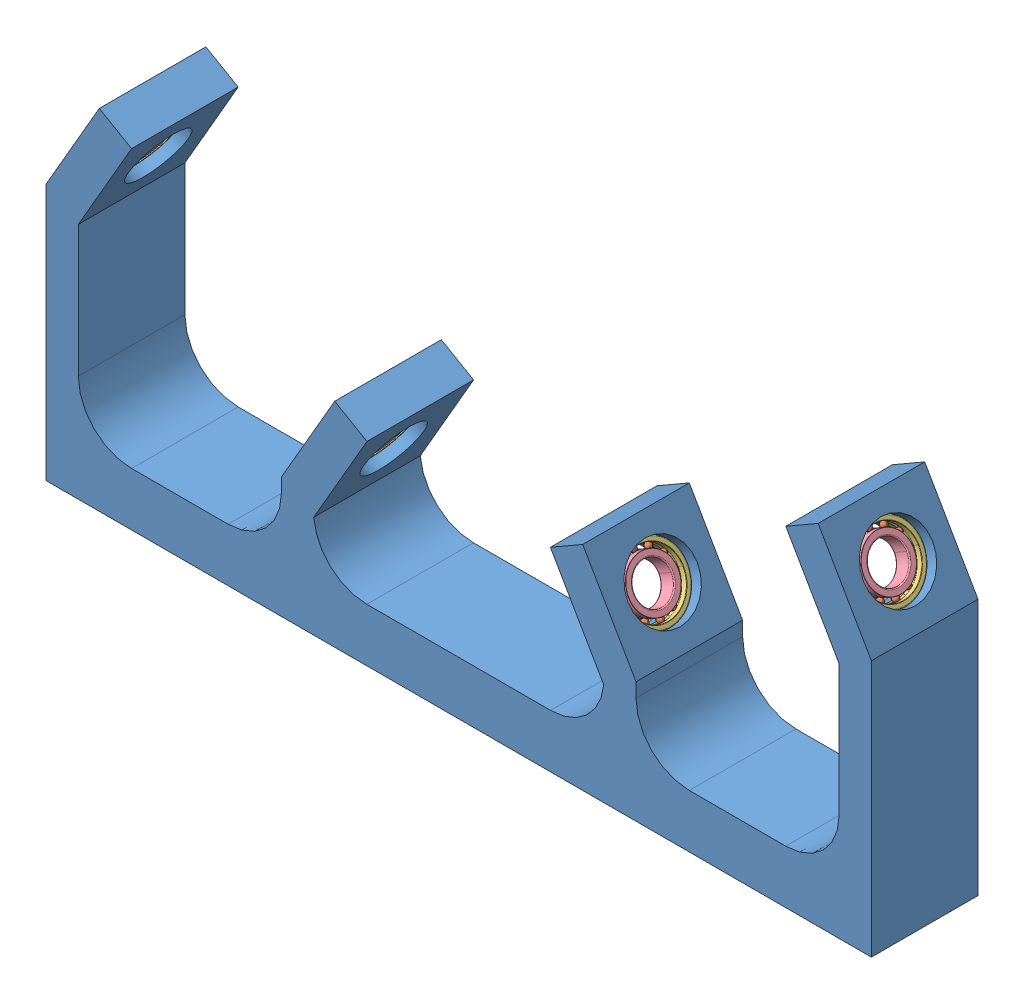
SolidWorks assembly Assemblage2, configuration Défaut. Lengths in mm.
Overall size (154.87 65.48 20).
61 component instances, 4 part files, 8 mates.
Components (placement in the parent):
- support rouleau-1: support rouleau [Défaut] at (-2.3977 -25.7602 154.8705) size (154.87 65.48 20)
- SKF_W_627_X-1: SKF_W_627_X [Default] at (-73.1009 15.0603 154.8705) x (0.866025 -0.5 0) z (0 0 1) size (3 13 13)
  - SKF_W_627_X_16-1: SKF_W_627_X_16 [Default] x (1 0 0) z (0 -0.5 0.866025) size (1.2 1.2 1.2)
  - SKF_W_627_X_16-2: SKF_W_627_X_16 [Default] x (1 0 0) z (0 -0.866025 0.5) size (1.2 1.2 1.2)
  - SKF_W_627_X_16-3: SKF_W_627_X_16 [Default] x (1 0 0) z (0 -1 0) size (1.2 1.2 1.2)
  - SKF_W_627_X_16-4: SKF_W_627_X_16 [Default] x (1 0 0) z (0 -0.866025 -0.5) size (1.2 1.2 1.2)
  - SKF_W_627_X_16-5: SKF_W_627_X_16 [Default] x (1 0 0) z (0 -0.5 -0.866025) size (1.2 1.2 1.2)
  - SKF_W_627_X_16-6: SKF_W_627_X_16 [Default] x (1 0 0) z (0 0 -1) size (1.2 1.2 1.2)
  - SKF_W_627_X_16-7: SKF_W_627_X_16 [Default] x (1 0 0) z (0 0.5 -0.866025) size (1.2 1.2 1.2)
  - SKF_W_627_X_16-8: SKF_W_627_X_16 [Default] x (1 0 0) z (0 0.866025 -0.5) size (1.2 1.2 1.2)
  - SKF_W_627_X_16-9: SKF_W_627_X_16 [Default] x (1 0 0) z (0 1 0) size (1.2 1.2 1.2)
  - SKF_W_627_X_16-10: SKF_W_627_X_16 [Default] x (1 0 0) z (0 0.866025 0.5) size (1.2 1.2 1.2)
  - SKF_W_627_X_16-11: SKF_W_627_X_16 [Default] x (1 0 0) z (0 0.5 0.866025) size (1.2 1.2 1.2)
  - SKF_W_627_X_16-12: SKF_W_627_X_16 [Default] at origin size (1.2 1.2 1.2)
  - SKF_W_627_X_29-1: SKF_W_627_X_29 [Default] at origin size (3 13 13)
  - SKF_W_627_X_31-1: SKF_W_627_X_31 [Default] at origin size (3 9.35 9.35)
- SKF_W_627_X-2: SKF_W_627_X [Default] at (21.5401 -11.9397 154.8705) x (0.866025 0.5 0) z (0 0 1) size (3 13 13)
  - SKF_W_627_X_16-1: SKF_W_627_X_16 [Default] x (1 0 0) z (0 -0.5 0.866025) size (1.2 1.2 1.2)
  - SKF_W_627_X_16-2: SKF_W_627_X_16 [Default] x (1 0 0) z (0 -0.866025 0.5) size (1.2 1.2 1.2)
  - SKF_W_627_X_16-3: SKF_W_627_X_16 [Default] x (1 0 0) z (0 -1 0) size (1.2 1.2 1.2)
  - SKF_W_627_X_16-4: SKF_W_627_X_16 [Default] x (1 0 0) z (0 -0.866025 -0.5) size (1.2 1.2 1.2)
  - SKF_W_627_X_16-5: SKF_W_627_X_16 [Default] x (1 0 0) z (0 -0.5 -0.866025) size (1.2 1.2 1.2)
  - SKF_W_627_X_16-6: SKF_W_627_X_16 [Default] x (1 0 0) z (0 0 -1) size (1.2 1.2 1.2)
  - SKF_W_627_X_16-7: SKF_W_627_X_16 [Default] x (1 0 0) z (0 0.5 -0.866025) size (1.2 1.2 1.2)
  - SKF_W_627_X_16-8: SKF_W_627_X_16 [Default] x (1 0 0) z (0 0.866025 -0.5) size (1.2 1.2 1.2)
  - SKF_W_627_X_16-9: SKF_W_627_X_16 [Default] x (1 0 0) z (0 1 0) size (1.2 1.2 1.2)
  - SKF_W_627_X_16-10: SKF_W_627_X_16 [Default] x (1 0 0) z (0 0.866025 0.5) size (1.2 1.2 1.2)
  - SKF_W_627_X_16-11: SKF_W_627_X_16 [Default] x (1 0 0) z (0 0.5 0.866025) size (1.2 1.2 1.2)
  - SKF_W_627_X_16-12: SKF_W_627_X_16 [Default] at origin size (1.2 1.2 1.2)
  - SKF_W_627_X_29-1: SKF_W_627_X_29 [Default] at origin size (3 13 13)
  - SKF_W_627_X_31-1: SKF_W_627_X_31 [Default] at origin size (3 9.35 9.35)
- SKF_W_627_X-3: SKF_W_627_X [Default] at (-28.9336 -10.4397 154.8705) x (0.866025 -0.5 0) z (0 0 1) size (3 13 13)
  - SKF_W_627_X_16-1: SKF_W_627_X_16 [Default] x (1 0 0) z (0 -0.5 0.866025) size (1.2 1.2 1.2)
  - SKF_W_627_X_16-2: SKF_W_627_X_16 [Default] x (1 0 0) z (0 -0.866025 0.5) size (1.2 1.2 1.2)
  - SKF_W_627_X_16-3: SKF_W_627_X_16 [Default] x (1 0 0) z (0 -1 0) size (1.2 1.2 1.2)
  - SKF_W_627_X_16-4: SKF_W_627_X_16 [Default] x (1 0 0) z (0 -0.866025 -0.5) size (1.2 1.2 1.2)
  - SKF_W_627_X_16-5: SKF_W_627_X_16 [Default] x (1 0 0) z (0 -0.5 -0.866025) size (1.2 1.2 1.2)
  - SKF_W_627_X_16-6: SKF_W_627_X_16 [Default] x (1 0 0) z (0 0 -1) size (1.2 1.2 1.2)
  - SKF_W_627_X_16-7: SKF_W_627_X_16 [Default] x (1 0 0) z (0 0.5 -0.866025) size (1.2 1.2 1.2)
  - SKF_W_627_X_16-8: SKF_W_627_X_16 [Default] x (1 0 0) z (0 0.866025 -0.5) size (1.2 1.2 1.2)
  - SKF_W_627_X_16-9: SKF_W_627_X_16 [Default] x (1 0 0) z (0 1 0) size (1.2 1.2 1.2)
  - SKF_W_627_X_16-10: SKF_W_627_X_16 [Default] x (1 0 0) z (0 0.866025 0.5) size (1.2 1.2 1.2)
  - SKF_W_627_X_16-11: SKF_W_627_X_16 [Default] x (1 0 0) z (0 0.5 0.866025) size (1.2 1.2 1.2)
  - SKF_W_627_X_16-12: SKF_W_627_X_16 [Default] at origin size (1.2 1.2 1.2)
  - SKF_W_627_X_29-1: SKF_W_627_X_29 [Default] at origin size (3 13 13)
  - SKF_W_627_X_31-1: SKF_W_627_X_31 [Default] at origin size (3 9.35 9.35)
- SKF_W_627_X-4: SKF_W_627_X [Default] at (65.7074 13.5603 154.8705) x (0.866025 0.5 0) z (0 0 1) size (3 13 13)
  - SKF_W_627_X_16-1: SKF_W_627_X_16 [Default] x (1 0 0) z (0 -0.5 0.866025) size (1.2 1.2 1.2)
  - SKF_W_627_X_16-2: SKF_W_627_X_16 [Default] x (1 0 0) z (0 -0.866025 0.5) size (1.2 1.2 1.2)
  - SKF_W_627_X_16-3: SKF_W_627_X_16 [Default] x (1 0 0) z (0 -1 0) size (1.2 1.2 1.2)
  - SKF_W_627_X_16-4: SKF_W_627_X_16 [Default] x (1 0 0) z (0 -0.866025 -0.5) size (1.2 1.2 1.2)
  - SKF_W_627_X_16-5: SKF_W_627_X_16 [Default] x (1 0 0) z (0 -0.5 -0.866025) size (1.2 1.2 1.2)
  - SKF_W_627_X_16-6: SKF_W_627_X_16 [Default] x (1 0 0) z (0 0 -1) size (1.2 1.2 1.2)
  - SKF_W_627_X_16-7: SKF_W_627_X_16 [Default] x (1 0 0) z (0 0.5 -0.866025) size (1.2 1.2 1.2)
  - SKF_W_627_X_16-8: SKF_W_627_X_16 [Default] x (1 0 0) z (0 0.866025 -0.5) size (1.2 1.2 1.2)
  - SKF_W_627_X_16-9: SKF_W_627_X_16 [Default] x (1 0 0) z (0 1 0) size (1.2 1.2 1.2)
  - SKF_W_627_X_16-10: SKF_W_627_X_16 [Default] x (1 0 0) z (0 0.866025 0.5) size (1.2 1.2 1.2)
  - SKF_W_627_X_16-11: SKF_W_627_X_16 [Default] x (1 0 0) z (0 0.5 0.866025) size (1.2 1.2 1.2)
  - SKF_W_627_X_16-12: SKF_W_627_X_16 [Default] at origin size (1.2 1.2 1.2)
  - SKF_W_627_X_29-1: SKF_W_627_X_29 [Default] at origin size (3 13 13)
  - SKF_W_627_X_31-1: SKF_W_627_X_31 [Default] at origin size (3 9.35 9.35)
Mates (geometry in assembly coordinates):
- Coaxiale1: concentric: cylinder of support rouleau-1 through (-20.2733 -15.4397 154.8705) axis (-0.866025 0.5 0) radius 6.5; cylinder of SKF_W_627_X-1/SKF_W_627_X_29-1 through (-70.5028 13.5603 154.8705) axis (0.866025 -0.5 0) radius 6.5
- Coïncidente1: coincident anti-aligned: circle of support rouleau-1; plane of SKF_W_627_X-1/SKF_W_627_X_29-1 through (-67.682 18.4461 154.8705) normal (0.866025 -0.5 0)
- Coaxiale2: concentric: cylinder of support rouleau-1 through (-20.2733 -15.4397 154.8705) axis (-0.866025 0.5 0) radius 6.5; cylinder of SKF_W_627_X-3/SKF_W_627_X_29-1 through (-26.3355 -11.9397 154.8705) axis (0.866025 -0.5 0) radius 6.5
- Coïncidente2: coincident anti-aligned: plane of support rouleau-1 through (-26.3355 -11.9397 154.8705) normal (-0.866025 0.5 0); plane of SKF_W_627_X-3/SKF_W_627_X_29-1 through (-23.5147 -7.0539 154.8705) normal (0.866025 -0.5 0)
- Coaxiale3: concentric: cylinder of support rouleau-1 through (15.478 -15.4397 154.8705) axis (0.866025 0.5 0) radius 6.5; cylinder of SKF_W_627_X-2/SKF_W_627_X_29-1 through (24.1382 -10.4397 154.8705) axis (0.866025 0.5 0) radius 6.5
- Coïncidente3: coincident anti-aligned: plane of support rouleau-1 through (21.5401 -11.9397 154.8705) normal (0.866025 0.5 0); plane of SKF_W_627_X-2/SKF_W_627_X_29-1 through (18.3901 -6.4838 154.8705) normal (-0.866025 -0.5 0)
- Coaxiale4: concentric: cylinder of support rouleau-1 through (15.478 -15.4397 154.8705) axis (0.866025 0.5 0) radius 6.5; cylinder of SKF_W_627_X-4/SKF_W_627_X_29-1 through (68.3055 15.0603 154.8705) axis (0.866025 0.5 0) radius 6.5
- Coïncidente4: coincident anti-aligned: plane of support rouleau-1 through (65.7074 13.5603 154.8705) normal (0.866025 0.5 0); plane of SKF_W_627_X-4/SKF_W_627_X_29-1 through (62.5574 19.0162 154.8705) normal (-0.866025 -0.5 0)
